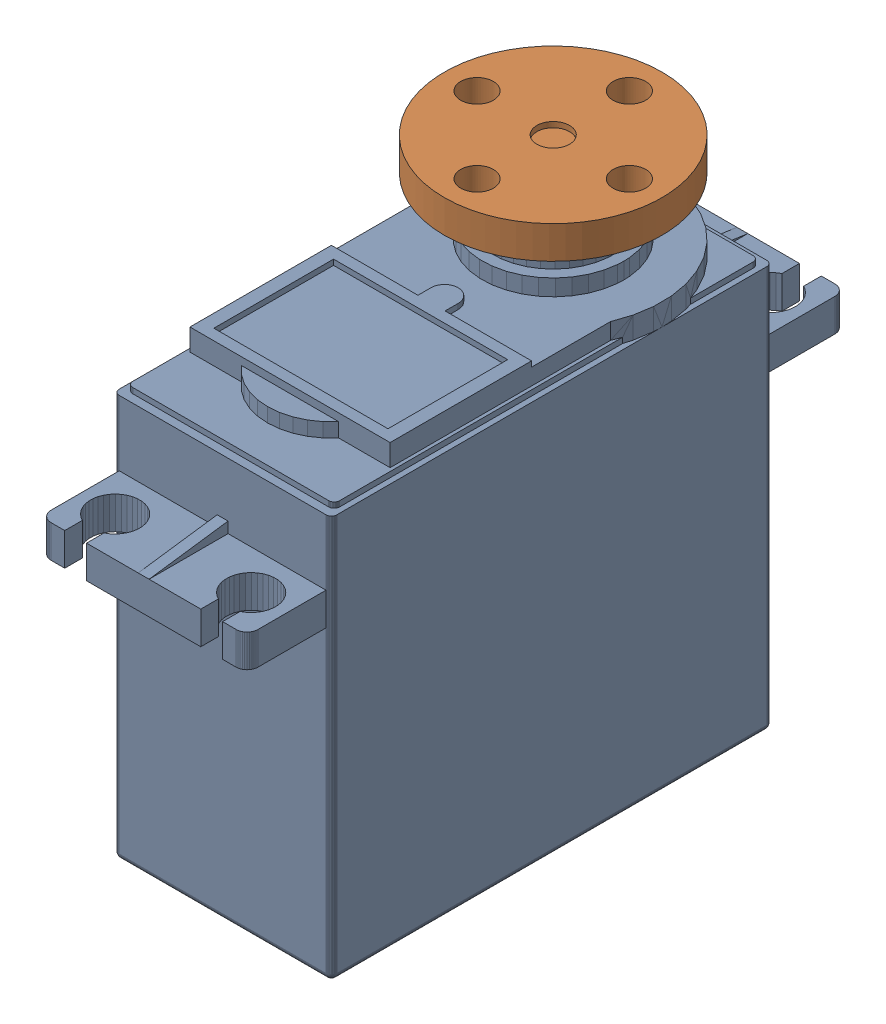
SolidWorks assembly Servo and metal horn v1, configuration Default. Lengths in mm.
Overall size (20 47.3 55.02).
3 component instances, 2 part files, 0 mates.
Components (placement in the parent):
- servo v7-1: servo v7 [Default] at (0 -3 -26) size (20 46.8 55.02)
  - Component3-1: Component3 [Default] at origin size (20 46.8 55.02)
- servo metal horn-1: servo metal horn [Default] at (0.0023 47.1264 -67.7367) x (1 0 0) z (0 0 -1) size (20 4.5 20)
